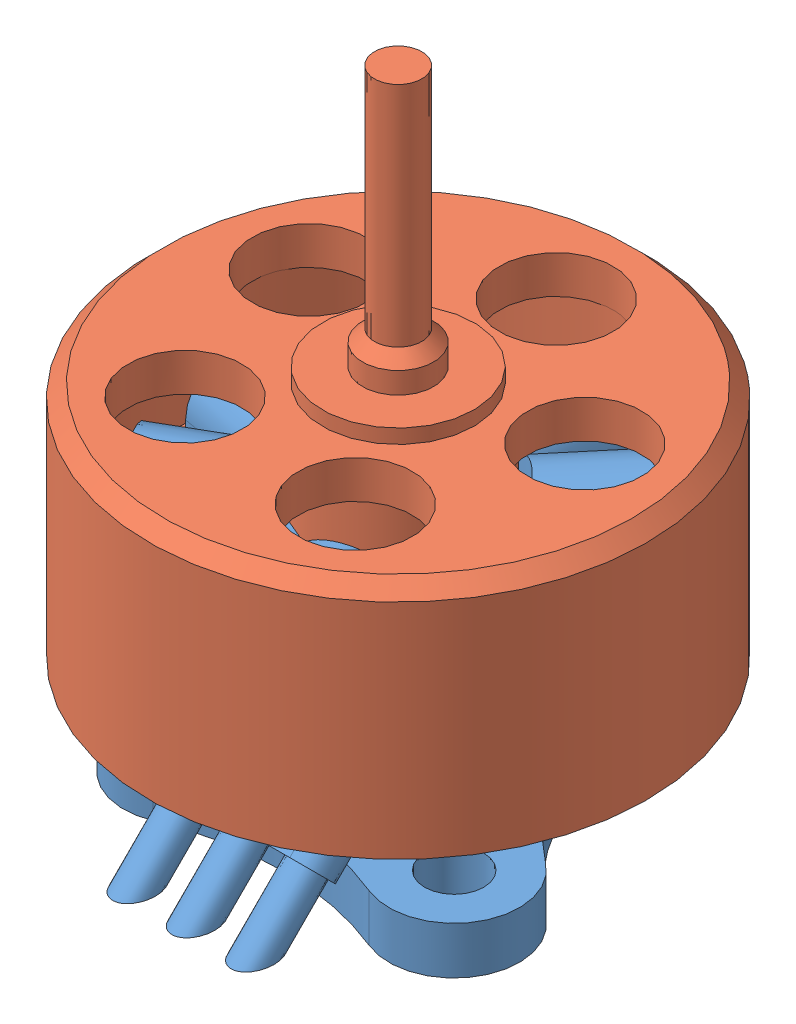
SolidWorks assembly Motor, configuration Default. Lengths in mm.
Overall size (14.75 14.8 14.75).
2 component instances, 2 part files, 5 mates.
Components (placement in the parent):
- Motor_Coils-1: Motor_Coils [Default] at origin size (8.75 6.11 9.61)
- Motor_Bell-1: Motor_Bell [Default] at (0 4.8 0) x (-0.782653 0 -0.622459) z (0.622459 0 -0.782653) size (10.5 14.8 10.5)
Mates (geometry in assembly coordinates):
- Coincident1: coordinate: point of Motor_Coils-1
- Concentric1: concentric aligned: cylinder of Motor_Coils-1 through (0 1 0) axis (0 -1 0) radius 0.75; cylinder of Motor_Bell-1 through (0 -1.3 0) axis (0 -1 0) radius 0.5
- Coincident3: coincident anti-aligned: plane of Motor_Coils-1 through (3.6673 5.4 -3.8494) normal (0 1 0); plane of Motor_Bell-1 through (0 5.4 0) normal (0 -1 0)
- Coincident15: coincident aligned: circle of Motor_Bell-1; plane of Prop_CCW-1 through (0 8.7 0) normal (0 -1 0)
- Concentric18: concentric anti-aligned: cylinder of Motor_Bell-1 through (0 -1.3 0) axis (0 -1 0) radius 0.5; cylinder of Prop_CCW-1 through (0 8.7 0) axis (0 1 0) radius 5
